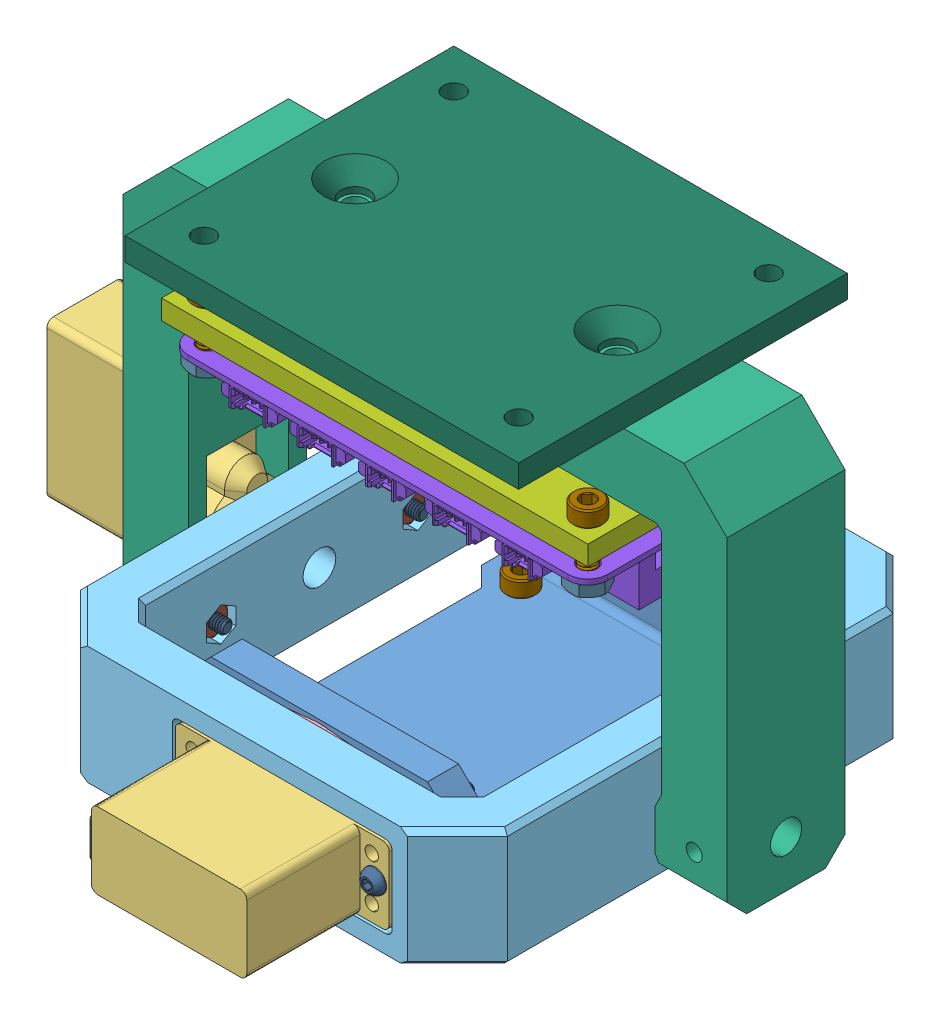
SolidWorks assembly New Gimbal Assembly, configuration Default. Lengths in mm.
Overall size (106.87 84.67 93.85).
50 component instances, 16 part files, 116 mates.
Components (placement in the parent):
- CyberCortexAdaptor-2: CyberCortexAdaptor [Default] at (-0.1011 139.3596 1.1859) x (1 0 0) z (0 1 0) size (638.36 379.45 266.79) (hidden)
- Platform4v2-1: Platform4v2 [Default] at origin size (40 15 53.5)
- Sensors-1: Sensors [Default] at (0 -2 0) x (0 0 1) z (0 1 0) size (42.16 34 19.1)
- Accurate Servo-1: Accurate Servo [Default] at (5.8302 9.5 55.48) x (0 -1 0) z (1 0 0) size (11.64 29.5 32.6)
- B1 Dual Horn-1: B1 Dual Horn [Default] at (0 9.5 25) x (1 0 0) z (0 -1 0) size (35 4.23 8)
- Pitch4v2-1: Pitch4v2 [Default] at (0.0002 9.5 1.1945) size (65.07 18 74.07)
- B1 Dual Horn-2: B1 Dual Horn [Default] at (-30.7853 9.5 1.1945) x (0 0 1) z (0 -1 0) size (35 4.23 8)
- Accurate Servo-2: Accurate Servo [Default] at (-61.2653 15.3302 1.1945) x (0 0 1) z (0 1 0) size (11.64 29.5 32.6)
- Rollo4-1: Rollo4 [Default] at (-0.1011 50.0651 1.1945) size (92.12 66.41 18)
- PCB mount4-1: PCB mount4 [Default] at (-0.1011 50.0651 1.1945) x (1 0 0) z (0 0 -1) size (65 3 34)
- MainBoard-1: MainBoard [Default] at (-0.1011 44.0651 1.1945) x (1 0 0) z (0 1 0) size (64 33 9.3)
- 91292A014 M2.5 cap screw-1: 91292A014 M2.5 cap screw [91292A014] at (14 -7 18) x (-0.52868 0 -0.848821) z (0 -1 0) size (4.5 4.5 13.01)
- 91292A014 M2.5 cap screw-2: 91292A014 M2.5 cap screw [91292A014] at (-14 -7 -18) x (-0.805817 0 0.592164) z (0 -1 0) size (4.5 4.5 13.01)
- 91292A014 M2.5 cap screw-3: 91292A014 M2.5 cap screw [91292A014] at (-14 -7 18) x (-0.43855 0 0.898707) z (0 -1 0) size (4.5 4.5 13.01)
- 91292A014 M2.5 cap screw-4: 91292A014 M2.5 cap screw [91292A014] at (14 -7 -18) x (-0.101959 0 -0.994789) z (0 -1 0) size (4.5 4.5 13.01)
- 92095A454_18-8 SS BUTTON-HEAD SOCKET CAP SCREW-1: 92095A454_18-8 SS BUTTON-HEAD SOCKET CAP SCREW [92095A454] at (15 9.5 28.08) size (3.5 3.5 9.53)
- 92095A454_18-8 SS BUTTON-HEAD SOCKET CAP SCREW-2: 92095A454_18-8 SS BUTTON-HEAD SOCKET CAP SCREW [92095A454] at (-15 9.5 28.08) size (3.5 3.5 9.53)
- 90725A010_ZINC-PLATED STEEL HIGH HEX NUT-1: 90725A010_ZINC-PLATED STEEL HIGH HEX NUT [90725A010] at (15 9.5 21) x (0.992261 -0.124169 0) z (0.124169 0.992261 0) size (4 2.31 4.62)
- 90725A010_ZINC-PLATED STEEL HIGH HEX NUT-2: 90725A010_ZINC-PLATED STEEL HIGH HEX NUT [90725A010] at (-15 9.5 21) x (-0.923728 -0.383049 0) z (-0.383049 0.923728 0) size (4 2.31 4.62)
- 90725A010_ZINC-PLATED STEEL HIGH HEX NUT-3: 90725A010_ZINC-PLATED STEEL HIGH HEX NUT [90725A010] at (-14 -3.8 18) size (4 2.31 4.62)
- 90725A010_ZINC-PLATED STEEL HIGH HEX NUT-4: 90725A010_ZINC-PLATED STEEL HIGH HEX NUT [90725A010] at (-14 -3.8 -18) x (0.23329 0 0.972407) z (-0.972407 0 0.23329) size (4 2.31 4.62)
- 90725A010_ZINC-PLATED STEEL HIGH HEX NUT-5: 90725A010_ZINC-PLATED STEEL HIGH HEX NUT [90725A010] at (14 -3.8 18) x (-0.260305 0 0.965526) z (-0.965526 0 -0.260305) size (4 2.31 4.62)
- 90725A010_ZINC-PLATED STEEL HIGH HEX NUT-6: 90725A010_ZINC-PLATED STEEL HIGH HEX NUT [90725A010] at (14 -3.8 -18) size (4 2.31 4.62)
- 92871A101_SS UNTHRD SPACER-1: 92871A101_SS UNTHRD SPACER [92871A101] at (14 -1 18) x (1 0 0) z (0 -1 0) size (4.5 4.5 2)
- 92871A101_SS UNTHRD SPACER-2: 92871A101_SS UNTHRD SPACER [92871A101] at (-14 -1 18) x (0.272629 0 -0.962119) z (0 -1 0) size (4.5 4.5 2)
- 92871A101_SS UNTHRD SPACER-3: 92871A101_SS UNTHRD SPACER [92871A101] at (-14 -1 -18) x (0.991798 0 0.127816) z (0 -1 0) size (4.5 4.5 2)
- 92871A101_SS UNTHRD SPACER-4: 92871A101_SS UNTHRD SPACER [92871A101] at (14 -1 -18) x (1 0 0) z (0 -1 0) size (4.5 4.5 2)
- GSI_0304_06_1-1: GSI_0304_06_1 [Default] at (35.0607 9.5 1.1945) x (0 0.000471 1) z (-1 0 0) size (6.35 6.35 9.53)
- GSI_0304_06_1-2: GSI_0304_06_1 [Default] at (0.0002 9.5 -28.8411) x (-0.923728 -0.383049 0) z (0 0 -1) size (6.35 6.35 9.53)
- 92095A454_18-8 SS BUTTON-HEAD SOCKET CAP SCREW-3: 92095A454_18-8 SS BUTTON-HEAD SOCKET CAP SCREW [92095A454] at (-33.8653 9.5 16.1945) x (0 0.110925 -0.993829) z (-1 0 0) size (3.5 3.5 9.53)
- 90725A010_ZINC-PLATED STEEL HIGH HEX NUT-7: 90725A010_ZINC-PLATED STEEL HIGH HEX NUT [90725A010] at (-27.5353 9.5 16.1945) x (0 0.866025 -0.5) z (0 0.5 0.866025) size (4 2.31 4.62)
- 92095A454_18-8 SS BUTTON-HEAD SOCKET CAP SCREW-4: 92095A454_18-8 SS BUTTON-HEAD SOCKET CAP SCREW [92095A454] at (-45.3153 29.4907 1.1945) x (0 0.820803 -0.571211) z (-1 0 0) size (3.5 3.5 9.53)
- 90725A010_ZINC-PLATED STEEL HIGH HEX NUT-8: 90725A010_ZINC-PLATED STEEL HIGH HEX NUT [90725A010] at (-38.0153 29.4907 1.1945) x (0 0.5 -0.866025) z (0 0.866025 0.5) size (4 2.31 4.62)
- 92095A454_18-8 SS BUTTON-HEAD SOCKET CAP SCREW-5: 92095A454_18-8 SS BUTTON-HEAD SOCKET CAP SCREW [92095A454] at (-8.3303 9.5 39.53) x (0.390186 -0.920736 0) z (0 0 1) size (3.5 3.5 9.53)
- 90725A010_ZINC-PLATED STEEL HIGH HEX NUT-9: 90725A010_ZINC-PLATED STEEL HIGH HEX NUT [90725A010] at (-8.3303 9.5 33.23) x (-0.5 0.866025 0) z (-0.866025 -0.5 0) size (4 2.31 4.62)
- 92095A454_18-8 SS BUTTON-HEAD SOCKET CAP SCREW-6: 92095A454_18-8 SS BUTTON-HEAD SOCKET CAP SCREW [92095A454] at (19.9907 9.5 39.53) size (3.5 3.5 9.53)
- 90725A010_ZINC-PLATED STEEL HIGH HEX NUT-10: 90725A010_ZINC-PLATED STEEL HIGH HEX NUT [90725A010] at (19.9907 9.5 33.23) x (-0.5 0.866025 0) z (-0.866025 -0.5 0) size (4 2.31 4.62)
- 92095A454_18-8 SS BUTTON-HEAD SOCKET CAP SCREW-7: 92095A454_18-8 SS BUTTON-HEAD SOCKET CAP SCREW [92095A454] at (-45.3153 1.1697 1.1945) x (0 0.381151 0.924513) z (-1 0 0) size (3.5 3.5 9.53)
- 90725A010_ZINC-PLATED STEEL HIGH HEX NUT-11: 90725A010_ZINC-PLATED STEEL HIGH HEX NUT [90725A010] at (-38.0153 1.1697 1.1945) x (0 0.5 -0.866025) z (0 -0.866025 -0.5) size (4 2.31 4.62)
- 92095A454_18-8 SS BUTTON-HEAD SOCKET CAP SCREW-8: 92095A454_18-8 SS BUTTON-HEAD SOCKET CAP SCREW [92095A454] at (-33.8653 9.5 -13.8055) x (0 0.990901 0.134594) z (-1 0 0) size (3.5 3.5 9.53)
- 90725A010_ZINC-PLATED STEEL HIGH HEX NUT-12: 90725A010_ZINC-PLATED STEEL HIGH HEX NUT [90725A010] at (-27.5353 9.5 -13.8055) x (0 0 -1) z (0 -1 0) size (4 2.31 4.62)
- 91292A014 M2.5 cap screw-5: 91292A014 M2.5 cap screw [91292A014] at (-29.1011 40.0651 14.6945) x (0.680452 0 -0.732792) z (0 -1 0) size (4.5 4.5 13.01)
- 91292A014 M2.5 cap screw-6: 91292A014 M2.5 cap screw [91292A014] at (28.8989 40.0651 -12.3055) x (-0.90747 0 -0.420117) z (0 -1 0) size (4.5 4.5 13.01)
- 91292A014 M2.5 cap screw-7: 91292A014 M2.5 cap screw [91292A014] at (28.8989 40.0651 14.6945) x (-0.933696 0 0.358068) z (0 -1 0) size (4.5 4.5 13.01)
- 91292A014 M2.5 cap screw-8: 91292A014 M2.5 cap screw [91292A014] at (-29.1011 40.0651 -12.3055) x (-0.999967 0 -0.008139) z (0 -1 0) size (4.5 4.5 13.01)
- 94150A310 M2.5 hex nut-1: 94150A310 M2.5 hex nut [94150A310] at (28.8989 42.2651 14.6945) x (0.822322 0 0.569023) z (0 1 0) size (5 5.77 2.25)
- 94150A310 M2.5 hex nut-2: 94150A310 M2.5 hex nut [94150A310] at (28.8989 42.2651 -12.3055) x (0.781798 0 -0.623532) z (0 1 0) size (5 5.77 2.25)
- 94150A310 M2.5 hex nut-3: 94150A310 M2.5 hex nut [94150A310] at (-29.1011 42.2651 14.6945) x (0.762284 0 0.647243) z (0 1 0) size (5 5.77 2.25)
- 94150A310 M2.5 hex nut-4: 94150A310 M2.5 hex nut [94150A310] at (-29.1011 42.2651 -12.3055) x (0.716837 0 -0.697241) z (0 1 0) size (5 5.77 2.25)
- Mounnting Plate 3D-1: Mounnting Plate 3D [Default] at (-0.1011 60.0651 1.1945) size (60 3.5 50.1)
Mates (geometry in assembly coordinates):
- Coincident2: coordinate: point of Platform4v2-1; point of assembly
- Distance1: distance = 2 mm: plane of Platform4v2-1 through (0 0 0) normal (0 -1 0); plane of Sensors-1 through (0 -2 0) normal (0 1 0)
- Concentric1: concentric: cylinder of Sensors-1 through (14 54.6306 18) axis (0 -1 0) radius 1.45; cylinder of Platform4v2-1 through (14 3 18) axis (0 -1 0) radius 1.4
- Concentric2: concentric: cylinder of Platform4v2-1 through (-14 3 -18) axis (0 -1 0) radius 1.4; cylinder of Sensors-1 through (-14 54.6306 -18) axis (0 -1 0) radius 1.45
- Concentric3: concentric: cylinder of Accurate Servo-1 through (0 9.5 25.98) axis (0 0 1) radius 2.5; circle of B1 Dual Horn-1
- Coincident4: coincident: plane of Accurate Servo-1 through (0 9.5 29.23) normal (0 0 -1); plane of B1 Dual Horn-1 through (0 9.5 29.23) normal (0 0 1)
- Concentric4: concentric: cylinder of Platform4v2-1 through (15 9.5 -26.751) axis (0 0 1) radius 1.2; cylinder of B1 Dual Horn-1 through (15 9.5 26.78) axis (0 0 1) radius 1.1
- Concentric5: concentric: cylinder of Platform4v2-1 through (-15 9.5 -26.751) axis (0 0 1) radius 1.2; cylinder of B1 Dual Horn-1 through (-15 9.5 26.78) axis (0 0 1) radius 1.1
- Coincident5: coincident: plane of Platform4v2-1 through (0 0 25) normal (0 0 1); plane of B1 Dual Horn-1 through (0 9.5 25) normal (0 0 -1)
- Concentric6: concentric: cylinder of Accurate Servo-1 through (19.9907 9.5 55.481) axis (0 0 -1) radius 1.016; cylinder of Pitch4v2-1 through (19.9907 9.5 -35.8421) axis (0 0 1) radius 1.1
- Concentric7: concentric: cylinder of Accurate Servo-1 through (-8.3303 9.5 55.481) axis (0 0 -1) radius 1.016; cylinder of Pitch4v2-1 through (-8.3303 9.5 -35.8421) axis (0 0 1) radius 1.1
- Coincident6: coincident: plane of Accurate Servo-1 through (-10.4698 3.68 36.23) normal (0 0 -1); plane of Pitch4v2-1 through (0.0002 9.5 36.23) normal (0 0 1)
- Concentric8: concentric: cylinder of B1 Dual Horn-2 through (-35.0153 9.5 1.1945) axis (1 0 0) radius 2.2; cylinder of Accurate Servo-2 through (-31.7653 9.5 1.1945) axis (-1 0 0) radius 2.5
- Coincident7: coincident: plane of B1 Dual Horn-2 through (-35.0153 9.5 1.1945) normal (-1 0 0); plane of Accurate Servo-2 through (-35.0153 9.5 1.1945) normal (1 0 0)
- Concentric9: concentric: cylinder of Pitch4v2-1 through (32.5367 9.5 -13.8055) axis (-1 0 0) radius 0.8; cylinder of B1 Dual Horn-2 through (-32.5653 9.5 -13.8055) axis (-1 0 0) radius 1.1
- Concentric10: concentric: cylinder of Pitch4v2-1 through (32.5367 9.5 16.1945) axis (-1 0 0) radius 0.8; cylinder of B1 Dual Horn-2 through (-32.5653 9.5 16.1945) axis (-1 0 0) radius 1.1
- Coincident8: coincident: plane of Pitch4v2-1 through (-30.7853 9.5 1.1945) normal (-1 0 0); plane of B1 Dual Horn-2 through (-30.7853 9.5 1.1945) normal (1 0 0)
- Concentric15: concentric: cylinder of Rollo4-1 through (9.8989 60.0651 1.1945) axis (0 1 0) radius 1.65; cylinder of PCB mount4-1 through (9.8989 47.0651 1.1945) axis (0 -1 0) radius 2.15
- Concentric16: concentric: cylinder of Rollo4-1 through (-10.1011 60.0651 1.1945) axis (0 1 0) radius 1.65; cylinder of PCB mount4-1 through (-10.1011 47.0651 1.1945) axis (0 -1 0) radius 2.15
- Coincident11: coincident: plane of Rollo4-1 through (-35.1011 50.0651 10.1945) normal (0 -1 0); plane of PCB mount4-1 through (-0.1011 50.0651 1.1945) normal (0 1 0)
- Concentric17: concentric: cylinder of Accurate Servo-2 through (-61.2663 29.4907 1.1945) axis (1 0 0) radius 1.016; cylinder of Rollo4-1 through (45.607 29.4907 1.1945) axis (-1 0 0) radius 1.1
- Concentric18: concentric: cylinder of Accurate Servo-2 through (-61.2663 1.1697 1.1945) axis (1 0 0) radius 1.016; cylinder of Rollo4-1 through (45.607 1.1697 1.1945) axis (-1 0 0) radius 1.1
- Coincident12: coincident: plane of Accurate Servo-2 through (-42.0153 31.6302 -4.6255) normal (1 0 0); plane of Rollo4-1 through (-42.0153 50.0651 1.1945) normal (-1 0 0)
- Concentric26: concentric: cylinder of Platform4v2-1 through (-14 3 -18) axis (0 -1 0) radius 1.4; cylinder of 91292A014 M2.5 cap screw-2 through (-14 5.5 -18) axis (0 -1 0) radius 2.25
- Concentric27: concentric: cylinder of Platform4v2-1 through (-14 3 -18) axis (0 -1 0) radius 1.4; cylinder of 91292A014 M2.5 cap screw-2 through (-14 5.5 -18) axis (0 -1 0) radius 2.25
- Coincident16: coincident: plane of Platform4v2-1 through (0 3 0) normal (0 1 0); plane of 91292A014 M2.5 cap screw-2 through (-14 3 -18) normal (0 -1 0)
- Concentric28: concentric: cylinder of Platform4v2-1 through (-14 3 18) axis (0 -1 0) radius 1.4; cylinder of 91292A014 M2.5 cap screw-3 through (-14 5.5 18) axis (0 -1 0) radius 2.25
- Coincident17: coincident: plane of Platform4v2-1 through (0 3 0) normal (0 1 0); plane of 91292A014 M2.5 cap screw-3 through (-14 3 18) normal (0 -1 0)
- Concentric29: concentric: cylinder of Platform4v2-1 through (14 3 -18) axis (0 -1 0) radius 1.4; cylinder of 91292A014 M2.5 cap screw-4 through (14 5.5 -18) axis (0 -1 0) radius 2.25
- Coincident18: coincident: plane of Platform4v2-1 through (0 3 0) normal (0 1 0); plane of 91292A014 M2.5 cap screw-4 through (14 3 -18) normal (0 -1 0)
- Concentric31: concentric: cylinder of Platform4v2-1 through (14 3 18) axis (0 -1 0) radius 1.4; cylinder of 91292A014 M2.5 cap screw-1 through (14 5.5 18) axis (0 -1 0) radius 2.25
- Coincident19: coincident: plane of Platform4v2-1 through (0 3 0) normal (0 1 0); plane of 91292A014 M2.5 cap screw-1 through (14 3 18) normal (0 -1 0)
- Concentric32: concentric: cylinder of B1 Dual Horn-1 through (-15 9.5 26.78) axis (0 0 1) radius 1.1; cylinder of 92095A454_18-8 SS BUTTON-HEAD SOCKET CAP SCREW-2 through (-15 9.5 28.08) axis (0 0 1) radius 1.75
- Concentric33: concentric: cylinder of B1 Dual Horn-1 through (15 9.5 26.78) axis (0 0 1) radius 1.1; cylinder of 92095A454_18-8 SS BUTTON-HEAD SOCKET CAP SCREW-1 through (15 9.5 28.08) axis (0 0 1) radius 1.75
- Coincident20: coincident: plane of B1 Dual Horn-1 through (0 9.5 26.78) normal (0 0 1); plane of 92095A454_18-8 SS BUTTON-HEAD SOCKET CAP SCREW-1 through (15 7.75 26.78) normal (0 0 -1)
- Coincident21: coincident: plane of B1 Dual Horn-1 through (0 9.5 26.78) normal (0 0 1); plane of 92095A454_18-8 SS BUTTON-HEAD SOCKET CAP SCREW-2 through (-15 7.75 26.78) normal (0 0 -1)
- Concentric34: concentric: circle of Platform4v2-1; circle of 90725A010_ZINC-PLATED STEEL HIGH HEX NUT-1
- Coincident22: coincident: plane of Platform4v2-1 through (0 0 22) normal (0 0 -1); plane of 90725A010_ZINC-PLATED STEEL HIGH HEX NUT-1 through (12.8721 8.6026 22) normal (0 0 1)
- Concentric35: concentric: circle of Platform4v2-1; circle of 90725A010_ZINC-PLATED STEEL HIGH HEX NUT-2
- Coincident23: coincident: plane of Platform4v2-1 through (0 0 22) normal (0 0 -1); plane of 90725A010_ZINC-PLATED STEEL HIGH HEX NUT-2 through (-12.7102 9.1995 22) normal (0 0 1)
- Concentric36: concentric: cylinder of 91292A014 M2.5 cap screw-1 through (14 5.5 18) axis (0 -1 0) radius 2.25; circle of 90725A010_ZINC-PLATED STEEL HIGH HEX NUT-5
- Coincident24: coincident: plane of Sensors-1 through (0 -2.8 0) normal (0 -1 0); plane of 90725A010_ZINC-PLATED STEEL HIGH HEX NUT-5 through (15.6355 -2.8 16.3695) normal (0 1 0)
- Concentric38: concentric: cylinder of 91292A014 M2.5 cap screw-4 through (14 5.5 -18) axis (0 -1 0) radius 2.25; circle of 90725A010_ZINC-PLATED STEEL HIGH HEX NUT-6
- Coincident25: coincident: plane of Sensors-1 through (0 -2.8 0) normal (0 -1 0); plane of 90725A010_ZINC-PLATED STEEL HIGH HEX NUT-6 through (12 -2.8 -19.1547) normal (0 1 0)
- Concentric40: concentric: cylinder of 91292A014 M2.5 cap screw-3 through (-14 5.5 18) axis (0 -1 0) radius 2.25; circle of 90725A010_ZINC-PLATED STEEL HIGH HEX NUT-3
- Coincident26: coincident: plane of Sensors-1 through (0 -2.8 0) normal (0 -1 0); plane of 90725A010_ZINC-PLATED STEEL HIGH HEX NUT-3 through (-16 -2.8 16.8453) normal (0 1 0)
- Concentric42: concentric: cylinder of 91292A014 M2.5 cap screw-2 through (-14 5.5 -18) axis (0 -1 0) radius 2.25; circle of 90725A010_ZINC-PLATED STEEL HIGH HEX NUT-4
- Coincident27: coincident: plane of Sensors-1 through (0 -2.8 0) normal (0 -1 0); plane of 90725A010_ZINC-PLATED STEEL HIGH HEX NUT-4 through (-13.3437 -2.8 -20.2142) normal (0 1 0)
- Concentric43: concentric: cylinder of 91292A014 M2.5 cap screw-1 through (14 5.5 18) axis (0 -1 0) radius 2.25; cylinder of 92871A101_SS UNTHRD SPACER-1 through (14 -2 18) axis (0 1 0) radius 1.35
- Coincident28: coincident: plane of Platform4v2-1 through (0 0 0) normal (0 -1 0); plane of 92871A101_SS UNTHRD SPACER-1 through (14 0 18) normal (0 1 0)
- Concentric45: concentric: cylinder of 91292A014 M2.5 cap screw-4 through (14 5.5 -18) axis (0 -1 0) radius 2.25; cylinder of 92871A101_SS UNTHRD SPACER-4 through (14 -2 -18) axis (0 1 0) radius 1.35
- Coincident29: coincident: plane of Platform4v2-1 through (0 0 0) normal (0 -1 0); plane of 92871A101_SS UNTHRD SPACER-4 through (14 0 -18) normal (0 1 0)
- Concentric48: concentric: cylinder of 91292A014 M2.5 cap screw-2 through (-14 5.5 -18) axis (0 -1 0) radius 2.25; cylinder of 92871A101_SS UNTHRD SPACER-3 through (-14 -2 -18) axis (0 1 0) radius 1.35
- Coincident30: coincident: plane of Platform4v2-1 through (0 0 0) normal (0 -1 0); plane of 92871A101_SS UNTHRD SPACER-3 through (-14 0 -18) normal (0 1 0)
- Concentric51: concentric: cylinder of 91292A014 M2.5 cap screw-3 through (-14 5.5 18) axis (0 -1 0) radius 2.25; cylinder of 92871A101_SS UNTHRD SPACER-2 through (-14 -2 18) axis (0 1 0) radius 1.35
- Coincident31: coincident: plane of Platform4v2-1 through (0 0 0) normal (0 -1 0); plane of 92871A101_SS UNTHRD SPACER-2 through (-14 0 18) normal (0 1 0)
- Angle1: planar angle = 0.785398 rad: plane of Rollo4-1 through (-0.1011 50.0651 -7.8055) normal (0 0 -1); plane of Pitch4v2-1 through (0.0002 18.5 1.1945) normal (0 1 0)
- Angle2: planar angle = 0.785398 rad: plane of Platform4v2-1 through (20 3 0) normal (1 0 0); plane of Pitch4v2-1 through (0.0002 0.5 1.1945) normal (0 -1 0)
- Concentric52: concentric: cylinder of Pitch4v2-1 through (-32.5363 9.5 1.1945) axis (1 0 0) radius 3.175; cylinder of GSI_0304_06_1-1 through (30.4482 9.5 1.1945) axis (-1 0 0) radius 3.175
- Coincident38: coincident: plane of GSI_0304_06_1-1 through (25.5357 9.5013 3.886) normal (-1 0 0); plane of Pitch4v2-1 through (25.5357 18.5 -25.3055) normal (-1 0 0)
- Concentric53: concentric: cylinder of Pitch4v2-1 through (0.0002 9.5 38.231) axis (0 0 -1) radius 3.175; cylinder of GSI_0304_06_1-2 through (0.0002 9.5 -33.4536) axis (0 0 -1) radius 3.175
- Coincident39: coincident: plane of Pitch4v2-1 through (-21.9998 18.5 -28.8411) normal (0 0 1); plane of GSI_0304_06_1-2 through (-2.6994 8.3806 -28.8411) normal (0 0 1)
- Concentric54: concentric: cylinder of Pitch4v2-1 through (32.5367 9.5 16.1945) axis (-1 0 0) radius 0.8; cylinder of 92095A454_18-8 SS BUTTON-HEAD SOCKET CAP SCREW-3 through (-33.8653 9.5 16.1945) axis (-1 0 0) radius 1.75
- Coincident40: coincident: plane of B1 Dual Horn-2 through (-32.5653 9.5 1.1945) normal (-1 0 0); plane of 92095A454_18-8 SS BUTTON-HEAD SOCKET CAP SCREW-3 through (-32.5653 11.2392 16.3886) normal (1 0 0)
- Concentric55: concentric: cylinder of 92095A454_18-8 SS BUTTON-HEAD SOCKET CAP SCREW-3 through (-33.8653 9.5 16.1945) axis (-1 0 0) radius 1.75; circle of 90725A010_ZINC-PLATED STEEL HIGH HEX NUT-7
- Coincident41: coincident: plane of Pitch4v2-1 through (-28.5353 9.5 1.1945) normal (1 0 0); plane of 90725A010_ZINC-PLATED STEEL HIGH HEX NUT-7 through (-28.5353 7.1906 16.1945) normal (-1 0 0)
- Parallel1: parallel: plane of Pitch4v2-1 through (-28.5353 8.201 13.9445) normal (0 0 1); plane of 90725A010_ZINC-PLATED STEEL HIGH HEX NUT-7 through (-28.5353 10.6547 14.1945) normal (0 0 -1)
- Concentric56: concentric: cylinder of Rollo4-1 through (45.607 29.4907 1.1945) axis (-1 0 0) radius 1.1; cylinder of 92095A454_18-8 SS BUTTON-HEAD SOCKET CAP SCREW-4 through (-45.3153 29.4907 1.1945) axis (-1 0 0) radius 1.75
- Coincident43: coincident: plane of Accurate Servo-2 through (-44.0153 31.6302 -4.6255) normal (-1 0 0); plane of 92095A454_18-8 SS BUTTON-HEAD SOCKET CAP SCREW-4 through (-44.0153 30.4903 2.6309) normal (1 0 0)
- Concentric57: concentric: cylinder of 92095A454_18-8 SS BUTTON-HEAD SOCKET CAP SCREW-4 through (-45.3153 29.4907 1.1945) axis (-1 0 0) radius 1.75; circle of 90725A010_ZINC-PLATED STEEL HIGH HEX NUT-8
- Parallel2: parallel: plane of Rollo4-1 through (-39.0153 29.4907 -1.4036) normal (0 -0.5 0.866025); plane of 90725A010_ZINC-PLATED STEEL HIGH HEX NUT-8 through (-39.0153 31.4907 0.0398) normal (0 0.5 -0.866025)
- Coincident45: coincident: plane of Rollo4-1 through (-39.0153 50.0651 1.1945) normal (1 0 0); plane of 90725A010_ZINC-PLATED STEEL HIGH HEX NUT-8 through (-39.0153 27.4907 2.3492) normal (-1 0 0)
- Concentric58: concentric: cylinder of Pitch4v2-1 through (-8.3303 9.5 -35.8421) axis (0 0 1) radius 1.1; cylinder of 92095A454_18-8 SS BUTTON-HEAD SOCKET CAP SCREW-5 through (-8.3303 9.5 39.53) axis (0 0 1) radius 1.75
- Coincident46: coincident: plane of Accurate Servo-1 through (-10.4698 3.68 38.23) normal (0 0 1); plane of 92095A454_18-8 SS BUTTON-HEAD SOCKET CAP SCREW-5 through (-9.9416 8.8172 38.23) normal (0 0 -1)
- Concentric59: concentric: cylinder of 92095A454_18-8 SS BUTTON-HEAD SOCKET CAP SCREW-5 through (-8.3303 9.5 39.53) axis (0 0 1) radius 1.75; circle of 90725A010_ZINC-PLATED STEEL HIGH HEX NUT-9
- Coincident47: coincident: plane of Pitch4v2-1 through (0.0002 9.5 34.23) normal (0 0 -1); plane of 90725A010_ZINC-PLATED STEEL HIGH HEX NUT-9 through (-6.3303 8.3453 34.23) normal (0 0 1)
- Parallel3: parallel: plane of Pitch4v2-1 through (-10.5803 8.201 34.23) normal (1 0 0); plane of 90725A010_ZINC-PLATED STEEL HIGH HEX NUT-9 through (-10.3303 8.3453 32.23) normal (-1 0 0)
- Concentric60: concentric: cylinder of Pitch4v2-1 through (19.9907 9.5 -35.8421) axis (0 0 1) radius 1.1; cylinder of 92095A454_18-8 SS BUTTON-HEAD SOCKET CAP SCREW-6 through (19.9907 9.5 39.53) axis (0 0 1) radius 1.75
- Coincident49: coincident: plane of Accurate Servo-1 through (22.1302 15.32 38.23) normal (0 0 1); plane of 92095A454_18-8 SS BUTTON-HEAD SOCKET CAP SCREW-6 through (19.9907 7.75 38.23) normal (0 0 -1)
- Concentric61: concentric: cylinder of 92095A454_18-8 SS BUTTON-HEAD SOCKET CAP SCREW-6 through (19.9907 9.5 39.53) axis (0 0 1) radius 1.75; circle of 90725A010_ZINC-PLATED STEEL HIGH HEX NUT-10
- Parallel4: parallel: plane of Pitch4v2-1 through (19.9907 6.9019 34.23) normal (0.5 0.866025 0); plane of 90725A010_ZINC-PLATED STEEL HIGH HEX NUT-10 through (19.9907 7.1906 32.23) normal (-0.5 -0.866025 0)
- Coincident51: coincident: plane of Pitch4v2-1 through (0.0002 9.5 34.23) normal (0 0 -1); plane of 90725A010_ZINC-PLATED STEEL HIGH HEX NUT-10 through (21.9907 8.3453 34.23) normal (0 0 1)
- Concentric62: concentric: cylinder of Rollo4-1 through (45.607 1.1697 1.1945) axis (-1 0 0) radius 1.1; cylinder of 92095A454_18-8 SS BUTTON-HEAD SOCKET CAP SCREW-7 through (-45.3153 1.1697 1.1945) axis (-1 0 0) radius 1.75
- Coincident57: coincident: plane of Accurate Servo-2 through (-44.0153 -0.9698 7.0145) normal (-1 0 0); plane of 92095A454_18-8 SS BUTTON-HEAD SOCKET CAP SCREW-7 through (-44.0153 -0.4482 1.8615) normal (1 0 0)
- Concentric63: concentric: cylinder of 92095A454_18-8 SS BUTTON-HEAD SOCKET CAP SCREW-7 through (-45.3153 1.1697 1.1945) axis (-1 0 0) radius 1.75; circle of 90725A010_ZINC-PLATED STEEL HIGH HEX NUT-11
- Parallel7: parallel: plane of Rollo4-1 through (-39.0153 -1.0803 2.4935) normal (0 1 0); plane of 90725A010_ZINC-PLATED STEEL HIGH HEX NUT-11 through (-37.0153 -0.8303 2.3492) normal (0 -1 0)
- Coincident59: coincident: plane of Rollo4-1 through (-39.0153 50.0651 1.1945) normal (1 0 0); plane of 90725A010_ZINC-PLATED STEEL HIGH HEX NUT-11 through (-39.0153 1.1697 3.5039) normal (-1 0 0)
- Concentric64: concentric: cylinder of Pitch4v2-1 through (32.5367 9.5 -13.8055) axis (-1 0 0) radius 0.8; cylinder of 92095A454_18-8 SS BUTTON-HEAD SOCKET CAP SCREW-8 through (-33.8653 9.5 -13.8055) axis (-1 0 0) radius 1.75
- Coincident60: coincident: plane of B1 Dual Horn-2 through (-32.5653 9.5 1.1945) normal (-1 0 0); plane of 92095A454_18-8 SS BUTTON-HEAD SOCKET CAP SCREW-8 through (-32.5653 9.2645 -12.0715) normal (1 0 0)
- Concentric65: concentric: cylinder of 92095A454_18-8 SS BUTTON-HEAD SOCKET CAP SCREW-8 through (-33.8653 9.5 -13.8055) axis (-1 0 0) radius 1.75; circle of 90725A010_ZINC-PLATED STEEL HIGH HEX NUT-12
- Parallel8: parallel: plane of Pitch4v2-1 through (-28.5353 10.799 -11.5555) normal (0 0 -1); plane of 90725A010_ZINC-PLATED STEEL HIGH HEX NUT-12 through (-26.5353 10.6547 -11.8055) normal (0 0 1)
- Coincident62: coincident: plane of Pitch4v2-1 through (-28.5353 9.5 1.1945) normal (1 0 0); plane of 90725A010_ZINC-PLATED STEEL HIGH HEX NUT-12 through (-28.5353 10.6547 -11.8055) normal (-1 0 0)
- Concentric68: concentric: cylinder of PCB mount4-1 through (-29.1011 47.0651 -12.3055) axis (0 -1 0) radius 1.35; cylinder of MainBoard-1 through (-29.1011 115.5471 -12.3055) axis (0 -1 0) radius 1.45
- Concentric69: concentric: cylinder of PCB mount4-1 through (28.8989 47.0651 14.6945) axis (0 -1 0) radius 1.35; cylinder of MainBoard-1 through (28.8989 115.5471 14.6945) axis (0 -1 0) radius 1.45
- Distance5: distance = 3 mm: plane of MainBoard-1 through (-0.1011 44.0651 1.1945) normal (0 1 0); plane of PCB mount4-1 through (-0.1011 47.0651 1.1945) normal (0 -1 0)
- Angle3: planar angle = 1.570796 rad: plane of Pitch4v2-1 through (0.0002 18.5 1.1945) normal (0 1 0); plane of Rollo4-1 through (-0.1011 50.0651 10.1945) normal (0 0 1)
- Angle4: planar angle = 0 rad: plane of Platform4v2-1 through (-20 15 26.75) normal (0 1 0); plane of Pitch4v2-1 through (0.0002 18.5 1.1945) normal (0 1 0)
- Concentric70: concentric: cylinder of PCB mount4-1 through (-29.1011 47.0651 14.6945) axis (0 -1 0) radius 1.35; cylinder of 91292A014 M2.5 cap screw-5 through (-29.1011 52.5651 14.6945) axis (0 -1 0) radius 2.25
- Coincident65: coincident: plane of PCB mount4-1 through (-0.1011 50.0651 1.1945) normal (0 1 0); plane of 91292A014 M2.5 cap screw-5 through (-29.1011 50.0651 14.6945) normal (0 -1 0)
- Concentric71: concentric: cylinder of PCB mount4-1 through (28.8989 47.0651 14.6945) axis (0 -1 0) radius 1.35; cylinder of 91292A014 M2.5 cap screw-7 through (28.8989 52.5651 14.6945) axis (0 -1 0) radius 2.25
- Coincident66: coincident: plane of PCB mount4-1 through (-0.1011 50.0651 1.1945) normal (0 1 0); plane of 91292A014 M2.5 cap screw-7 through (28.8989 50.0651 14.6945) normal (0 -1 0)
- Concentric72: concentric: cylinder of PCB mount4-1 through (28.8989 47.0651 -12.3055) axis (0 -1 0) radius 1.35; cylinder of 91292A014 M2.5 cap screw-6 through (28.8989 52.5651 -12.3055) axis (0 -1 0) radius 2.25
- Coincident67: coincident: plane of PCB mount4-1 through (-0.1011 50.0651 1.1945) normal (0 1 0); plane of 91292A014 M2.5 cap screw-6 through (28.8989 50.0651 -12.3055) normal (0 -1 0)
- Concentric73: concentric: cylinder of PCB mount4-1 through (-29.1011 47.0651 -12.3055) axis (0 -1 0) radius 1.35; cylinder of 91292A014 M2.5 cap screw-8 through (-29.1011 52.5651 -12.3055) axis (0 -1 0) radius 2.25
- Coincident68: coincident: plane of PCB mount4-1 through (-0.1011 50.0651 1.1945) normal (0 1 0); plane of 91292A014 M2.5 cap screw-8 through (-29.1011 50.0651 -12.3055) normal (0 -1 0)
- Concentric74: concentric: cylinder of 91292A014 M2.5 cap screw-5 through (-29.1011 52.5651 14.6945) axis (0 -1 0) radius 2.25; circle of 94150A310 M2.5 hex nut-3
- Coincident69: coincident: plane of MainBoard-1 through (-0.1011 43.2651 1.1945) normal (0 -1 0); plane of 94150A310 M2.5 hex nut-3 through (-30.0726 43.2651 11.9761) normal (0 1 0)
- Concentric76: concentric: cylinder of 91292A014 M2.5 cap screw-7 through (28.8989 52.5651 14.6945) axis (0 -1 0) radius 2.25; circle of 94150A310 M2.5 hex nut-1
- Coincident70: coincident: plane of MainBoard-1 through (-0.1011 43.2651 1.1945) normal (0 -1 0); plane of 94150A310 M2.5 hex nut-1 through (27.6644 43.2651 12.085) normal (0 1 0)
- Concentric77: concentric: cylinder of 91292A014 M2.5 cap screw-6 through (28.8989 52.5651 -12.3055) axis (0 -1 0) radius 2.25; circle of 94150A310 M2.5 hex nut-2
- Coincident71: coincident: plane of MainBoard-1 through (-0.1011 43.2651 1.1945) normal (0 -1 0); plane of 94150A310 M2.5 hex nut-2 through (26.0444 43.2651 -11.8751) normal (0 1 0)
- Concentric78: concentric: cylinder of 91292A014 M2.5 cap screw-8 through (-29.1011 52.5651 -12.3055) axis (0 -1 0) radius 2.25; circle of 94150A310 M2.5 hex nut-4
- Coincident72: coincident: plane of MainBoard-1 through (-0.1011 43.2651 1.1945) normal (0 -1 0); plane of 94150A310 M2.5 hex nut-4 through (-31.8996 43.2651 -11.5971) normal (0 1 0)
- Concentric79: concentric: cylinder of Rollo4-1 through (19.8989 60.0651 1.1945) axis (0 1 0) radius 1.65; cylinder of Mounnting Plate 3D-1 through (19.8989 63.5651 1.1945) axis (0 1 0) radius 2.15
- Concentric80: concentric: cylinder of Rollo4-1 through (-20.1011 60.0651 1.1945) axis (0 1 0) radius 1.65; cylinder of Mounnting Plate 3D-1 through (-20.1011 63.5651 1.1945) axis (0 1 0) radius 2.15
- Coincident73: coincident: plane of Rollo4-1 through (-39.2433 60.0651 10.1945) normal (0 1 0); plane of Mounnting Plate 3D-1 through (-0.1011 60.0651 1.1945) normal (0 -1 0)
